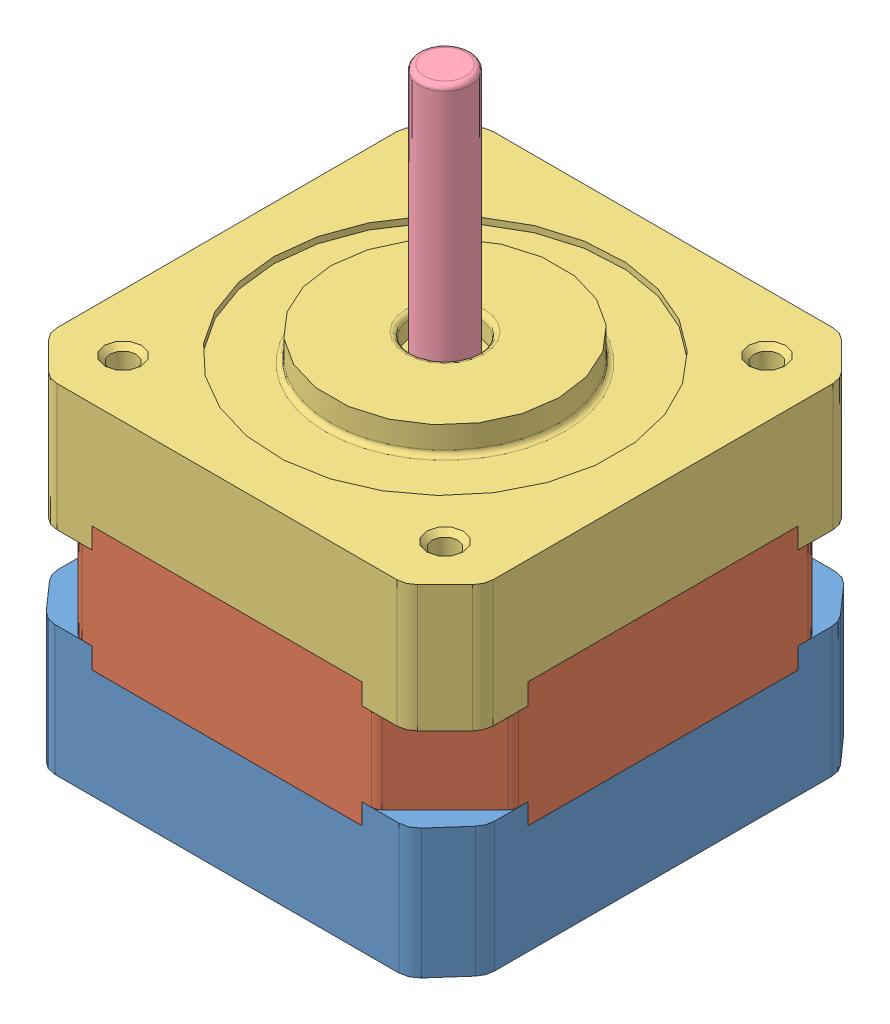
SolidWorks assembly Stepper Motor NEMA17, configuration Default. Lengths in mm.
Overall size (42 57 42).
8 component instances, 5 part files, 16 mates.
Components (placement in the parent):
- Stepper Motor NEMA17 Bottom-1: Stepper Motor NEMA17 Bottom [Default] at (16.7503 15.4206 31.8405) x (1 0 0) z (0 1 0) size (42 42 12.5)
- Stepper Motor NEMA17 Middle-1: Stepper Motor NEMA17 Middle [Default] at (16.7503 37.9206 31.8405) x (1 0 0) z (0 -1 0) size (42 42 12)
- Stepper Motor NEMA17 Top-1: Stepper Motor NEMA17 Top [Default] at (16.7503 48.1206 31.8405) x (1 0 0) z (0 -1 0) size (42 42 14.2)
- Stepper Motor NEMA17 Shaft-1: Stepper Motor NEMA17 Shaft [Default] at (16.7503 72.4206 31.8405) x (-0.646525 0 -0.762893) z (0 -1 0) size (5 5 57)
- pan head cross recess screw_iso-1: pan head cross recess screw_iso [ISO 7045 - M2.5 x 3 - Z --- 3N] at (1.2503 15.4206 47.3405) x (0 1 0) z (0 0 1) size (5.05 5 5)
- pan head cross recess screw_iso-2: pan head cross recess screw_iso [ISO 7045 - M2.5 x 3 - Z --- 3N] at (32.2503 15.4206 47.3405) x (0 1 0) z (0 0 1) size (5.05 5 5)
- pan head cross recess screw_iso-3: pan head cross recess screw_iso [ISO 7045 - M2.5 x 3 - Z --- 3N] at (1.2503 15.4206 16.3405) x (0 1 0) z (0 0 1) size (5.05 5 5)
- pan head cross recess screw_iso-4: pan head cross recess screw_iso [ISO 7045 - M2.5 x 3 - Z --- 3N] at (32.2503 15.4206 16.3405) x (0 1 0) z (0 0 1) size (5.05 5 5)
Mates (geometry in assembly coordinates):
- Coincident1: coincident anti-aligned: plane of Stepper Motor NEMA17 Bottom-1 through (-4.2497 25.9206 18.8405) normal (0 1 0); plane of Stepper Motor NEMA17 Middle-1 through (16.7503 25.9206 31.8405) normal (0 -1 0)
- Coincident2: coincident aligned: plane of Stepper Motor NEMA17 Bottom-1 through (37.7503 27.9206 48.8533) normal (1 0 0); plane of Stepper Motor NEMA17 Middle-1 through (37.7503 31.9206 17.4851) normal (1 0 0)
- Coincident3: coincident aligned: plane of Stepper Motor NEMA17 Bottom-1 through (-0.7153 27.9206 52.8405) normal (0 0 1); plane of Stepper Motor NEMA17 Middle-1 through (2.395 31.9206 52.8405) normal (0 0 1)
- Coincident4: coincident anti-aligned: plane of Stepper Motor NEMA17 Middle-1 through (2.395 35.9206 10.8405) normal (0 1 0); plane of Stepper Motor NEMA17 Top-1 through (16.7503 35.9206 31.8405) normal (0 -1 0)
- Coincident5: coincident aligned: plane of Stepper Motor NEMA17 Middle-1 through (37.7503 31.9206 17.4851) normal (1 0 0); plane of Stepper Motor NEMA17 Top-1 through (37.7503 35.9206 14.6567) normal (1 0 0)
- Coincident6: coincident aligned: plane of Stepper Motor NEMA17 Middle-1 through (2.395 31.9206 52.8405) normal (0 0 1); plane of Stepper Motor NEMA17 Top-1 through (-0.4334 35.9206 52.8405) normal (0 0 1)
- Concentric1: concentric aligned: cylinder of Stepper Motor NEMA17 Top-1 through (16.7503 35.9206 31.8405) axis (0 1 0) radius 2.5; cylinder of Stepper Motor NEMA17 Shaft-1 through (16.7503 15.4206 31.8405) axis (0 1 0) radius 2.5
- Distance1: distance = 57 mm anti-aligned: plane of Stepper Motor NEMA17 Shaft-1 through (16.7503 72.4206 31.8405) normal (0 1 0); plane of Stepper Motor NEMA17 Bottom-1 through (16.7503 15.4206 31.8405) normal (0 -1 0)
- Concentric2: concentric aligned: cylinder of Stepper Motor NEMA17 Bottom-1 through (1.2503 15.4206 47.3405) axis (0 -1 0) radius 1.45; cylinder of pan head cross recess screw_iso-1 through (1.2503 -9.9794 47.3405) axis (0 -1 0) radius 2.5
- Coincident8: coincident anti-aligned: plane of Stepper Motor NEMA17 Bottom-1 through (2.7003 17.5206 47.3405) normal (0 -1 0); plane of pan head cross recess screw_iso-1 through (0.0003 17.5206 47.3405) normal (0 1 0)
- Concentric3: concentric aligned: cylinder of Stepper Motor NEMA17 Bottom-1 through (32.2503 15.4206 47.3405) axis (0 -1 0) radius 1.45; cylinder of pan head cross recess screw_iso-2 through (32.2503 -9.9794 47.3405) axis (0 -1 0) radius 2.5
- Coincident9: coincident anti-aligned: plane of Stepper Motor NEMA17 Bottom-1 through (33.7003 17.5206 47.3405) normal (0 -1 0); plane of pan head cross recess screw_iso-2 through (31.0003 17.5206 47.3405) normal (0 1 0)
- Concentric4: concentric aligned: cylinder of Stepper Motor NEMA17 Bottom-1 through (1.2503 15.4206 16.3405) axis (0 -1 0) radius 1.45; cylinder of pan head cross recess screw_iso-3 through (1.2503 -9.9794 16.3405) axis (0 -1 0) radius 2.5
- Coincident10: coincident anti-aligned: plane of Stepper Motor NEMA17 Bottom-1 through (2.7003 17.5206 16.3405) normal (0 -1 0); plane of pan head cross recess screw_iso-3 through (0.0003 17.5206 16.3405) normal (0 1 0)
- Concentric5: concentric aligned: cylinder of Stepper Motor NEMA17 Bottom-1 through (32.2503 15.4206 16.3405) axis (0 -1 0) radius 1.45; cylinder of pan head cross recess screw_iso-4 through (32.2503 -9.9794 16.3405) axis (0 -1 0) radius 2.5
- Coincident11: coincident anti-aligned: plane of Stepper Motor NEMA17 Bottom-1 through (33.7003 17.5206 16.3405) normal (0 -1 0); plane of pan head cross recess screw_iso-4 through (31.0003 17.5206 16.3405) normal (0 1 0)
